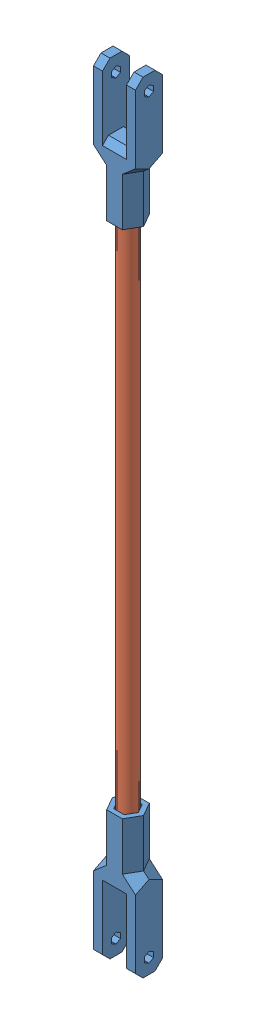
SolidWorks assembly Link Arm Assy, configuration Default. Lengths in mm.
Overall size (14 260 9).
3 component instances, 2 part files, 6 mates.
Components (placement in the parent):
- clevis-1: clevis [Default] at origin size (14 45 9)
- clevis-2: clevis [Default] at (0 -210 9) x (1 0 0) z (0 0 -1) size (14 45 9)
- Carbon Tube-1: Carbon Tube [Default] at (0 0 4.5) x (-1 0 0) z (0 -1 0) size (6 6 210)
Mates (geometry in assembly coordinates):
- Concentric25: concentric anti-aligned: line of clevis-2 through (0 -239.5374 4.5) axis (0 -1 0); cylinder of Carbon Tube-1 through (0 -210 4.5) axis (0 1 0) radius 3
- Coincident47: coincident anti-aligned: plane of clevis-2 through (-7 -210 0) normal (0 1 0); plane of Carbon Tube-1 through (0 -210 4.5) normal (0 -1 0)
- Coincident48: coincident anti-aligned: line of clevis-1 through (0 29.5374 4.5) axis (0 1 0); line of clevis-2 through (0 -239.5374 4.5) axis (0 -1 0)
- Coincident49: coincident aligned: plane of clevis-1 through (0 0 0) normal (0 0 -1); plane of clevis-2 through (0 -210 0) normal (0 0 -1)
- Coincident50: coincident anti-aligned: plane of clevis-1 through (-7 0 9) normal (0 -1 0); plane of Carbon Tube-1 through (0 0 4.5) normal (0 1 0)
- Coincident54: coincident anti-aligned: plane of Carbon Tube-1; plane of assembly through (0 0 0) normal (1 0 0)
